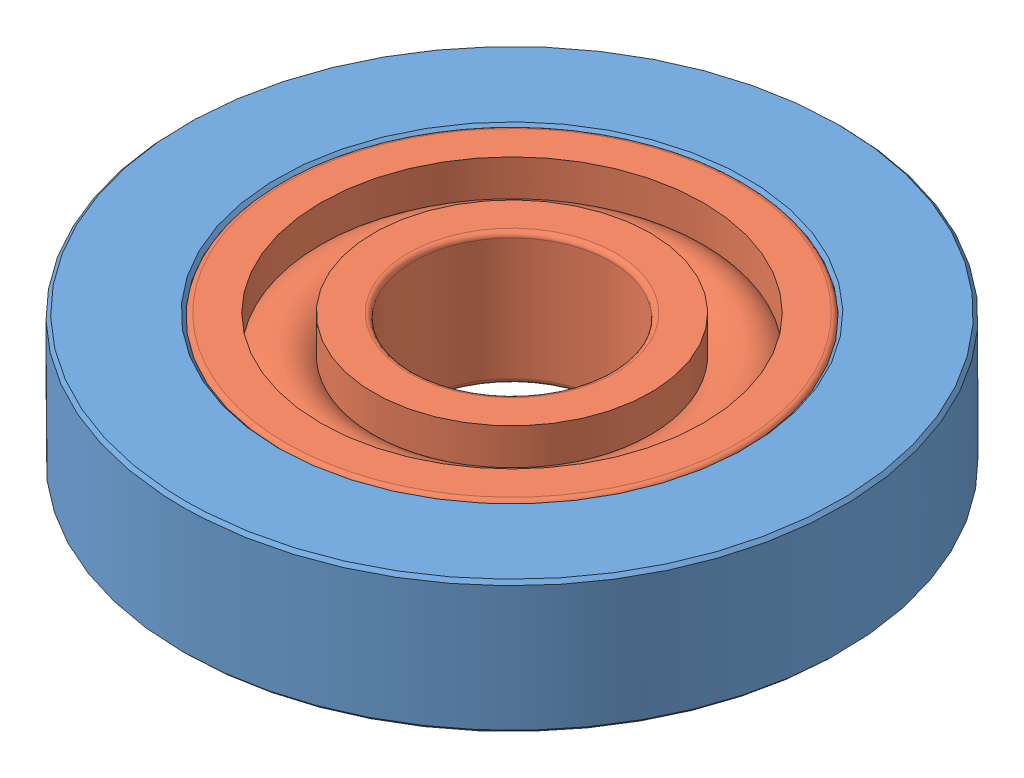
SolidWorks assembly Lezaj_s_Prstenom, configuration Default. Lengths in mm.
Overall size (40 8 40).
2 component instances, 2 part files, 2 mates.
Components (placement in the parent):
- Prsten_za_Zatezac-1: Prsten_za_Zatezac [Default] at (3.7834 70.1427 107.8727) size (40 8 40)
- radial ball bearing_68_skf-1: radial ball bearing_68_skf [SKF - 6001 - 10,SI,NC,10_68] at (3.7834 70.1427 107.8727) x (0 1 0) z (0 0 1) size (8 28 28)
Mates (geometry in assembly coordinates):
- Concentric1: concentric anti-aligned: cylinder of Prsten_za_Zatezac-1 through (3.7834 85.1427 107.8727) axis (0 -1 0) radius 14; cylinder of radial ball bearing_68_skf-1 through (3.7834 49.5052 107.8727) axis (0 1 0) radius 14
- Coincident1: coincident aligned: plane of Prsten_za_Zatezac-1 through (3.7834 70.1427 107.8727) normal (0 1 0); plane of radial ball bearing_68_skf-1 through (3.7834 70.1427 107.8727) normal (0 1 0)
